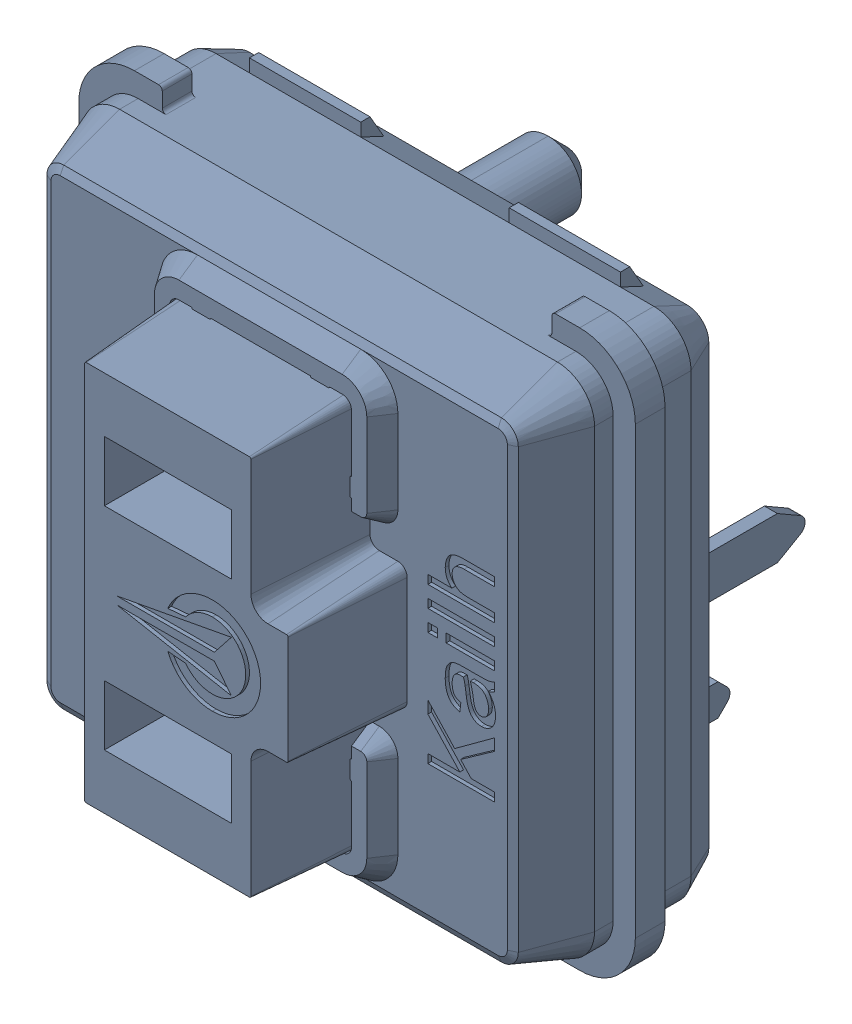
SolidWorks assembly SW7_1.step, configuration Default. Lengths in mm.
Overall size (15 15 11.1).
2 component instances, 2 part files, 0 mates.
Components (placement in the parent):
- Kailh LP Choc Burnt Orange_1.step-3: Kailh LP Choc Burnt Orange_1.step [Default] at (465.9499 258.5268 2.7) x (1 0 0) z (0 -1 0) size (15 11.1 15)
- WS2812-2020_1.step-3: WS2812-2020_1.step [Default] at (461.3087 258.6334 0.3) x (0 1 0) z (1 0 0) size (2.2 0.86 2)
